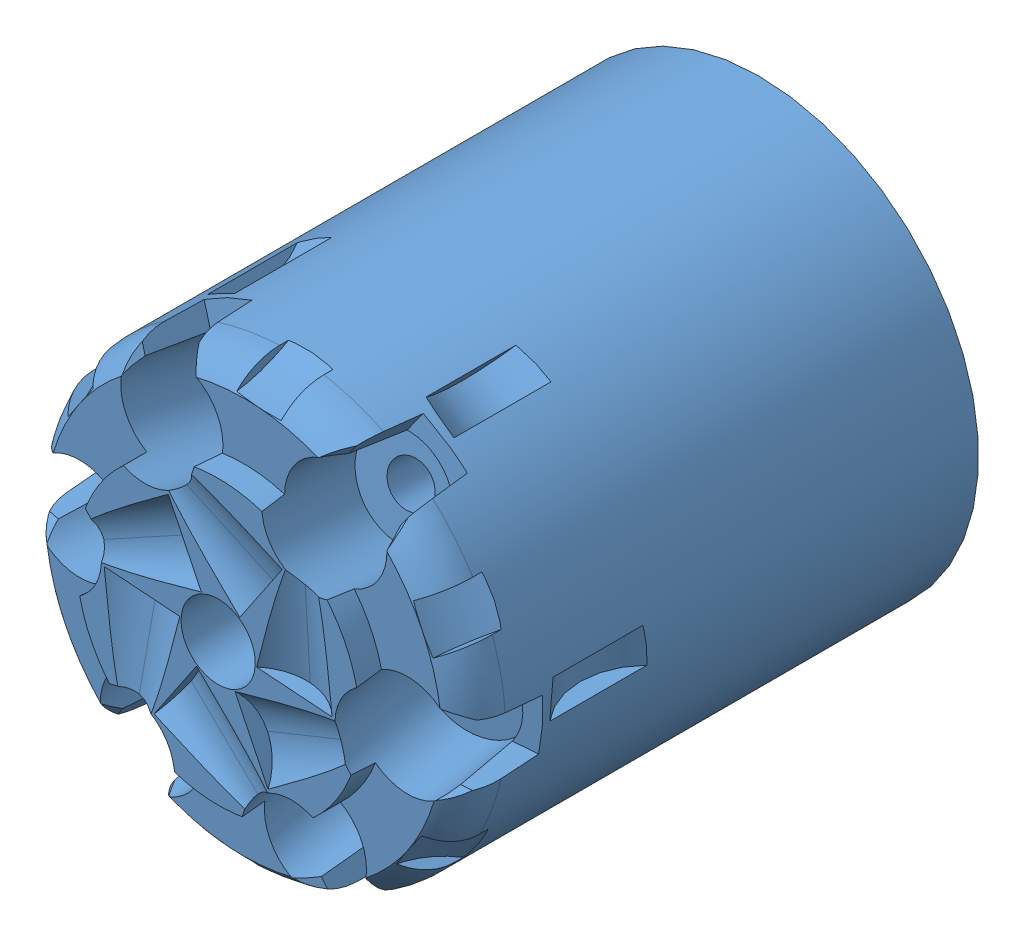
SolidWorks assembly Cylinder_inner_piston.44, configuration Default. Lengths in mm.
Overall size (76.91 85.64 77.53).
14 component instances, 4 part files, 5 mates.
Components (placement in the parent):
- 5mm-1: 5mm [Default] at (0.2237 0.2935 0.3421)
- Cylinder 1858-1: Cylinder 1858 [Default] at (-136.1766 -273.2413 216.2716) x (0.216059 0.319043 -0.922784) z (0.827999 -0.56073 0) size (60.74 55.75 42.2)
- Inner_cylinder.44-8: Inner_cylinder.44 [Default] at (12.8911 -0.6159 -1.3643) x (0.594907 -0.803795 0) z (0 0 1) size (11.4 11.4 19.82)
- Piston.44-7: Piston.44 [Default] at (12.8911 -0.6159 29.6822) x (0.802966 0.596025 0) z (0 0 -1) size (9.4 9.4 17)
- Inner_cylinder.44-9: Inner_cylinder.44 [Default] at (7.345 10.8091 -1.3643) x (0.99356 0.113307 0) z (0 0 1) size (11.4 11.4 19.82)
- Inner_cylinder.44-10: Inner_cylinder.44 [Default] at (-5.3224 11.7185 -1.3643) x (0.398653 0.917102 0) z (0 0 1) size (11.4 11.4 19.82)
- Inner_cylinder.44-11: Inner_cylinder.44 [Default] at (-12.4437 1.2029 -1.3643) x (-0.594907 0.803795 0) z (0 0 1) size (11.4 11.4 19.82)
- Inner_cylinder.44-12: Inner_cylinder.44 [Default] at (-6.8975 -10.2221 -1.3643) x (-0.99356 -0.113307 0) z (0 0 1) size (11.4 11.4 19.82)
- Inner_cylinder.44-13: Inner_cylinder.44 [Default] at (5.7699 -11.1315 -1.3643) x (-0.398653 -0.917102 0) z (0 0 1) size (11.4 11.4 19.82)
- Piston.44-8: Piston.44 [Default] at (7.345 10.8091 29.6822) x (-0.11469 0.993401 0) z (0 0 -1) size (9.4 9.4 17)
- Piston.44-9: Piston.44 [Default] at (-5.3224 11.7185 29.6822) x (-0.917656 0.397377 0) z (0 0 -1) size (9.4 9.4 17)
- Piston.44-10: Piston.44 [Default] at (-12.4437 1.2029 29.6822) x (-0.802966 -0.596025 0) z (0 0 -1) size (9.4 9.4 17)
- Piston.44-11: Piston.44 [Default] at (-6.8975 -10.2221 29.6822) x (0.11469 -0.993401 0) z (0 0 -1) size (9.4 9.4 17)
- Piston.44-12: Piston.44 [Default] at (5.7699 -11.1315 29.6822) x (0.917656 -0.397377 0) z (0 0 -1) size (9.4 9.4 17)
Mates (geometry in assembly coordinates):
- Concentric1: concentric: circle of 5mm-1; circle of Cylinder 1858-1
- Lock1: lock: unknown of Cylinder 1858-1
- Concentric6: concentric: cylinder of Inner_cylinder.44-8 through (12.8911 -0.6159 -3.6663) axis (0 0 1) radius 4.7; cylinder of Piston.44-7 through (12.8911 -0.6159 12.6822) axis (0 0 1) radius 4.09
- Concentric7: concentric: cylinder of Cylinder 1858-1 through (12.8911 -0.6159 15.2083) axis (0 0 -1) radius 5.7; cylinder of Inner_cylinder.44-8 through (12.8911 -0.6159 29.6357) axis (0 0 -1) radius 5.7
- Concentric8: concentric: circle of Cylinder 1858-1; cylinder of Inner_cylinder.44-8 through (12.8911 -0.6159 29.6357) axis (0 0 -1) radius 5.7
